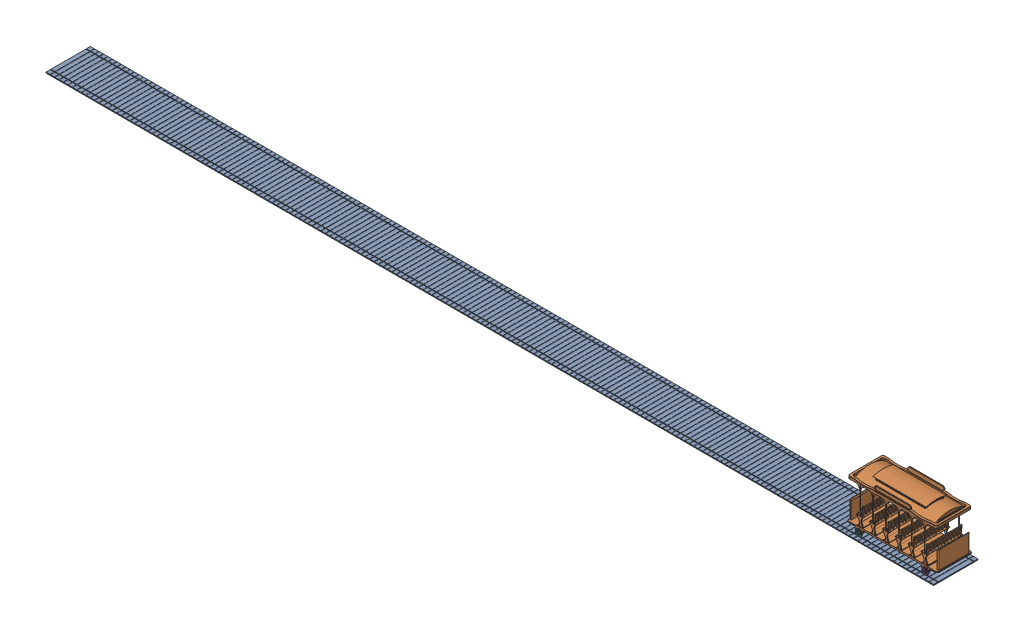
SolidWorks assembly Streetcar on Track, configuration Default. Lengths in mm.
Overall size (2000 122.93 100).
5 component instances, 3 part files, 3 mates.
Components (placement in the parent):
- Streetcar Track-1: Streetcar Track [Default] at (-26.4843 61.9853 550.2293) size (2000 2 100)
- Streetcar Assembly-1: Streetcar Assembly [Default] at (846.7654 38.7853 450.7442) size (204 122.93 84) (flexible)
  - Streetcar-1: Streetcar [Default] at (22.652 90.7 59.4851) size (204 115.5 80)
  - Streetcar Wheels-1: Streetcar Wheels [Default] at (-52.348 31.7 138.4851) x (0.567108 0.823643 0) z (0 0 1) size (15 15 84)
  - Streetcar Wheels-2: Streetcar Wheels [Default] at (97.652 31.7 138.4851) x (-0.003921 0.999992 0) z (0 0 1) size (15 15 84)
Mates (geometry in assembly coordinates):
- Coincident1: coincident anti-aligned: plane of Streetcar Track-1 through (973.5157 62.9853 589.2293) normal (0 0 1); plane of Streetcar Assembly-1/Streetcar Wheels-2 through (944.4173 70.4853 589.2293) normal (0 0 -1)
- Tangent1: tangent anti-aligned: plane of Streetcar Track-1 through (-26.4843 62.9853 550.2293) normal (0 1 0); cylinder of Streetcar Assembly-1/Streetcar Wheels-2 through (944.4173 70.4853 590.7293) axis (0 0 -1) radius 7.5
- Tangent2: tangent anti-aligned: plane of Streetcar Track-1 through (-26.4843 62.9853 550.2293) normal (0 1 0); cylinder of Streetcar Assembly-1/Streetcar Wheels-1 through (794.4173 70.4853 590.7293) axis (0 0 -1) radius 7.5
